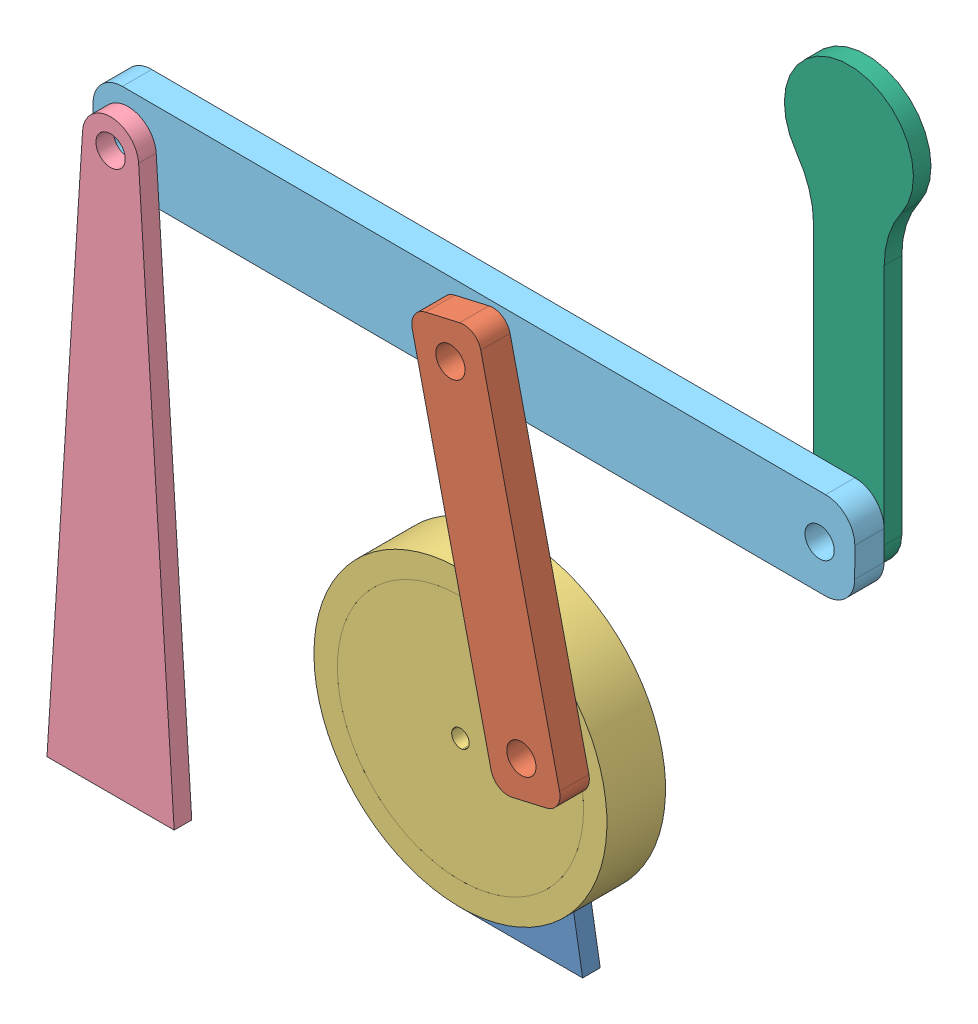
SolidWorks assembly All, configuration Default. Lengths in mm.
Overall size (139.87 162.68 18).
6 component instances, 6 part files, 13 mates.
Components (placement in the parent):
- fixed link short-1: fixed link short [По умолчанию] at (-12.0977 24.9058 16.6421) size (21.71 40 3)
- link-1: link [По умолчанию] at (-11.7339 58.3104 29.6421) x (-0.224164 0.974551 0) z (0 0 1) size (66 12 5)
- pulley-1: pulley [По умолчанию] at (16.3393 35.8722 19.6421) x (0.905758 0.423795 0) z (0 0 1) size (50 50 10)
- fixed link long-1: fixed link long [По умолчанию] at (-68.8044 84.9058 29.6421) size (21.71 100 3)
- long link-1: long link [По умолчанию] at (-47.7914 104.4404 24.6421) x (0.999996 -0.002828 0) z (0 0 1) size (130 15 5)
- load-1: load [По умолчанию] at (49.1951 151.6663 21.6421) size (22.03 74.04 3)
Mates (geometry in assembly coordinates):
- Concentric1: concentric aligned: cylinder of fixed link-1 through (-12.0977 35 19.6421) axis (0 0 -1) radius 1.5; cylinder of pulley-1 through (-12.0977 35 89.039) axis (0 0 -1) radius 1.5
- Coincident1: coincident anti-aligned: plane of fixed link-1 through (-12.0977 35.2082 19.6421) normal (0 0 1); plane of pulley-1 through (-12.0977 35 19.6421) normal (0 0 -1)
- Coincident2: coincident anti-aligned: plane of link-1 through (1.049 38.6084 29.6421) normal (0 0 -1); plane of pulley-1 through (-12.0977 35 29.6421) normal (0 0 1)
- Concentric2: concentric aligned: cylinder of link-1 through (3.3002 42.2045 34.6421) axis (0 0 -1) radius 2.5; cylinder of pulley-1 through (3.3002 42.2045 89.039) axis (0 0 -1) radius 2.5
- Parallel1: parallel aligned: plane of link-1 through (1.049 38.6084 29.6421) normal (0 0 -1); plane of fixed link long-1 through (-68.8044 95.2082 29.6421) normal (0 0 -1)
- Coincident6: coincident aligned: plane of link-1 through (1.049 38.6084 29.6421) normal (0 0 -1); plane of fixed link long-1 through (-68.8044 95.2082 29.6421) normal (0 0 -1)
- Parallel2: parallel aligned: plane of fixed link short-1 through (-1.2441 0 19.6421) normal (0 -1 0); plane of fixed link long-1 through (-57.9509 0 32.6421) normal (0 -1 0)
- Concentric3: concentric aligned: cylinder of fixed link long-1 through (-68.8044 95 32.6421) axis (0 0 -1) radius 2.5; cylinder of long link-1 through (-68.8044 95 29.6421) axis (0 0 -1) radius 2.5
- Coincident8: coincident anti-aligned: plane of fixed link long-1 through (-68.8044 95.2082 29.6421) normal (0 0 -1); plane of long link-1 through (-69.7973 97.5028 29.6421) normal (0 0 1)
- Concentric4: concentric aligned: cylinder of link-1 through (-8.8047 94.8303 34.6421) axis (0 0 -1) radius 2.5; cylinder of long link-1 through (-8.8047 94.8303 29.6421) axis (0 0 -1) radius 2.2234
- Coincident9: coincident aligned: plane of fixed link short-1 through (-1.2441 0 19.6421) normal (0 -1 0); plane of fixed link long-1 through (-57.9509 0 32.6421) normal (0 -1 0)
- Concentric5: concentric aligned: cylinder of long link-1 through (49.1951 94.6663 29.6421) axis (0 0 -1) radius 2.5; cylinder of load-1 through (49.1951 94.6663 24.6421) axis (0 0 -1) radius 2.5
- Coincident10: coincident anti-aligned: plane of long link-1 through (-69.7973 97.5028 24.6421) normal (0 0 -1); plane of load-1 through (71.2 136.03 24.6421) normal (0 0 1)
